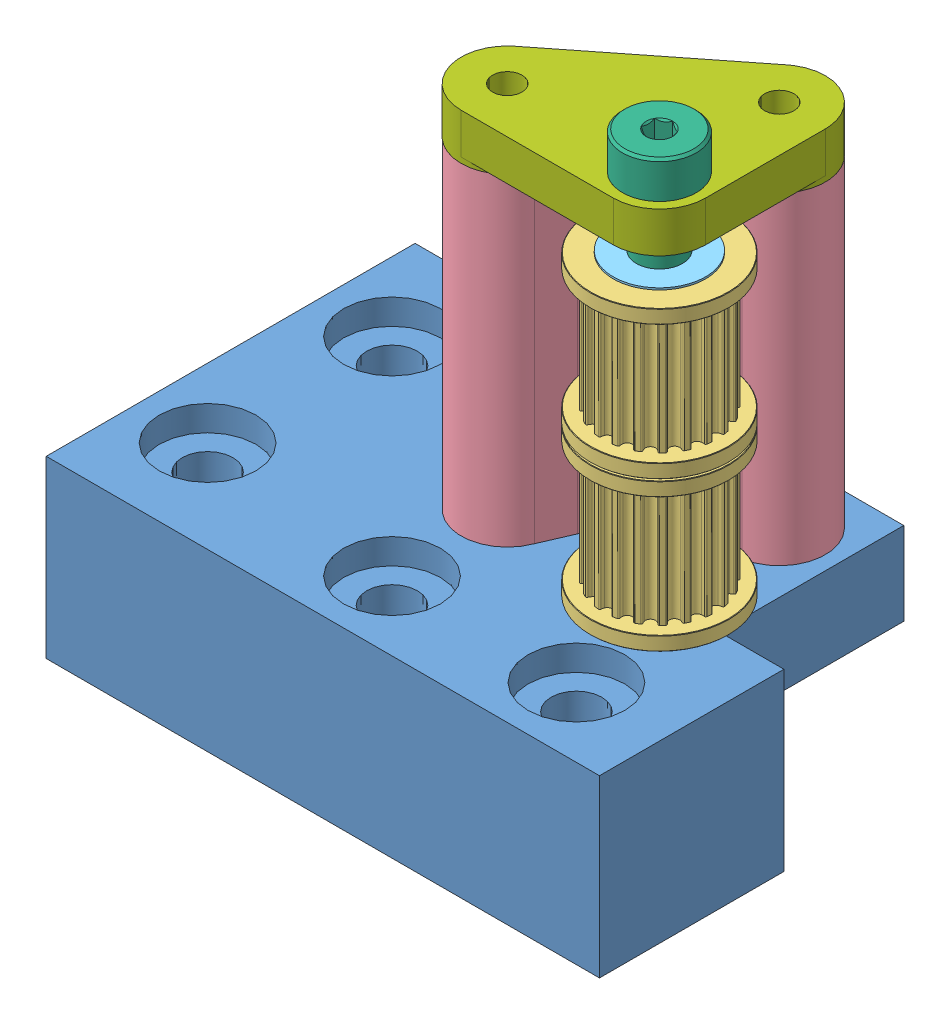
SolidWorks assembly double_pulley_corner_block_right_big, configuration Default. Lengths in mm.
Overall size (60 63 42.07).
10 component instances, 7 part files, 20 mates.
Components (placement in the parent):
- double_pulley_corner_block_right-1: double_pulley_corner_block_right [Default] at origin size (60 19 40)
- m4_heat_set_insert_long_94180A353-1: m4_heat_set_insert_long_94180A353 [94180A353] at (106.5 19 -20) size (6.35 8.38 6.35)
- Gates_20T_12mm_toothed_idler_5mm_bore-1: Gates_20T_12mm_toothed_idler_5mm_bore [Default] at (106.5 27.7758 -20) x (0.786472 0 -0.617626) z (0.617626 0 0.786472) size (15 16 15)
- double_pulley_reinforcement_plate_support-1: double_pulley_reinforcement_plate_support [Default] at (93.8609 54 -36.0419) x (0.233994 0 -0.972238) z (0 -1 0) size (26.5 23 35)
- m5_shim_0.2mm_thick_98089A246-1: m5_shim_0.2mm_thick_98089A246 [98089A246] at (106.5 19.2 -20) x (-0.837169 0 -0.546944) z (-0.546944 0 0.837169) size (10 0.2 10)
- m4_shoulder_screw_5mm_d_40mm_l-1: m4_shoulder_screw_5mm_d_40mm_l [90278A375] at (106.5 63 -20) x (1 0 0) z (0 1 0) size (8 8 49.24)
- back_pulley_reinforcement_plate-1: back_pulley_reinforcement_plate [Right Corner Pulley Reinforcement Plate] at (116.5 54.6 -20) size (26.5 5 23)
- m5_shim_0.2mm_thick_98089A246-2: m5_shim_0.2mm_thick_98089A246 [98089A246] at (106.5 35.4 -20) x (-0.837169 0 -0.546944) z (-0.546944 0 0.837169) size (10 0.2 10)
- Gates_20T_12mm_toothed_idler_5mm_bore-2: Gates_20T_12mm_toothed_idler_5mm_bore [Default] at (106.5 43.9758 -20) x (0.786472 0 -0.617626) z (0.617626 0 0.786472) size (15 16 15)
- m5_shim_0.2mm_thick_98089A246-3: m5_shim_0.2mm_thick_98089A246 [98089A246] at (106.5 51.6 -20) x (-0.837169 0 -0.546944) z (-0.546944 0 0.837169) size (10 0.2 10)
Mates (geometry in assembly coordinates):
- Coincident1: coincident aligned: plane of double_pulley_corner_block_right-1 through (120 19 0) normal (0 1 0); plane of m4_heat_set_insert_long_94180A353-1 through (106.5 19 -20) normal (0 1 0)
- Concentric1: concentric aligned: circle of double_pulley_corner_block_right-1; circle of m4_heat_set_insert_long_94180A353-1
- Coincident2: coincident anti-aligned: plane of double_pulley_corner_block_right-1 through (120 19 0) normal (0 1 0); plane of m5_shim_0.2mm_thick_98089A246-1 through (106.5 19 -20) normal (0 -1 0)
- Coincident3: coincident anti-aligned: plane of m4_heat_set_insert_long_94180A353-1 through (106.5 19 -20) normal (0 1 0); plane of m4_shoulder_screw_5mm_d_40mm_l-1 through (106.5 19 -17.5) normal (0 -1 0)
- Concentric2: concentric anti-aligned: cylinder of double_pulley_corner_block_right-1; cylinder of m4_shoulder_screw_5mm_d_40mm_l-1 through (106.5 14 -20) axis (0 -1 0) radius 2.5
- Coincident4: coincident aligned: circle of m5_shim_0.2mm_thick_98089A246-1; cylinder of m4_shoulder_screw_5mm_d_40mm_l-1 through (106.5 14 -20) axis (0 -1 0) radius 2.5
- Concentric3: concentric aligned: cylinder of Gates_20T_12mm_toothed_idler_5mm_bore-1 through (106.5 14.8876 -20) axis (0 -1 0) radius 2.5; cylinder of m4_shoulder_screw_5mm_d_40mm_l-1 through (106.5 14 -20) axis (0 -1 0) radius 2.5
- Coincident5: coincident anti-aligned: plane of Gates_20T_12mm_toothed_idler_5mm_bore-1 through (106.5 19.2 -20) normal (0 -1 0); plane of m5_shim_0.2mm_thick_98089A246-1 through (106.5 19.2 -20) normal (0 1 0)
- Coincident6: coincident anti-aligned: plane of Gates_20T_12mm_toothed_idler_5mm_bore-1 through (106.5 35.2 -20) normal (0 1 0); plane of m5_shim_0.2mm_thick_98089A246-2 through (106.5 35.2 -20) normal (0 -1 0)
- Concentric4: concentric aligned: cylinder of m4_shoulder_screw_5mm_d_40mm_l-1 through (106.5 14 -20) axis (0 -1 0) radius 2.5; cylinder of m5_shim_0.2mm_thick_98089A246-2 through (106.5 35.4 -20) axis (0 -1 0) radius 2.5
- Coincident8: coincident anti-aligned: plane of m5_shim_0.2mm_thick_98089A246-2 through (106.5 35.4 -20) normal (0 1 0); plane of Gates_20T_12mm_toothed_idler_5mm_bore-2 through (106.5 35.4 -20) normal (0 -1 0)
- Concentric5: concentric aligned: cylinder of m4_shoulder_screw_5mm_d_40mm_l-1 through (106.5 14 -20) axis (0 -1 0) radius 2.5; cylinder of Gates_20T_12mm_toothed_idler_5mm_bore-2 through (106.5 31.0876 -20) axis (0 -1 0) radius 2.5
- Concentric6: concentric aligned: cylinder of m4_shoulder_screw_5mm_d_40mm_l-1 through (106.5 14 -20) axis (0 -1 0) radius 2.5; cylinder of back_pulley_reinforcement_plate-1 through (106.5 56.17 -20) axis (0 -1 0) radius 2.5
- Coincident9: coincident anti-aligned: plane of m4_shoulder_screw_5mm_d_40mm_l-1 through (106.5 59 -16) normal (0 -1 0); plane of back_pulley_reinforcement_plate-1 through (90 59 -20) normal (0 1 0)
- Concentric7: concentric aligned: cylinder of double_pulley_corner_block_right-1 through (90 0 -20) axis (0 -1 0) radius 1.7; cylinder of back_pulley_reinforcement_plate-1 through (90 56.17 -20) axis (0 -1 0) radius 1.6
- Coincident10: coincident anti-aligned: plane of double_pulley_corner_block_right-1 through (120 19 0) normal (0 1 0); plane of double_pulley_reinforcement_plate_support-1 through (93.8609 19 -36.0419) normal (0 -1 0)
- Concentric8: concentric anti-aligned: cylinder of double_pulley_reinforcement_plate_support-1 through (90 19 -20) axis (0 1 0) radius 1.6; cylinder of back_pulley_reinforcement_plate-1 through (90 56.17 -20) axis (0 -1 0) radius 1.6
- Concentric9: concentric anti-aligned: cylinder of double_pulley_corner_block_right-1 through (106.5 10 -33) axis (0 -1 0) radius 1.7; cylinder of double_pulley_reinforcement_plate_support-1 through (106.5 19 -33) axis (0 1 0) radius 1.6
- Coincident11: coincident anti-aligned: plane of Gates_20T_12mm_toothed_idler_5mm_bore-2 through (106.5 51.4 -20) normal (0 1 0); plane of m5_shim_0.2mm_thick_98089A246-3 through (106.5 51.4 -20) normal (0 -1 0)
- Concentric10: concentric aligned: cylinder of m4_shoulder_screw_5mm_d_40mm_l-1 through (106.5 14 -20) axis (0 -1 0) radius 2.5; cylinder of m5_shim_0.2mm_thick_98089A246-3 through (106.5 51.6 -20) axis (0 -1 0) radius 2.5
